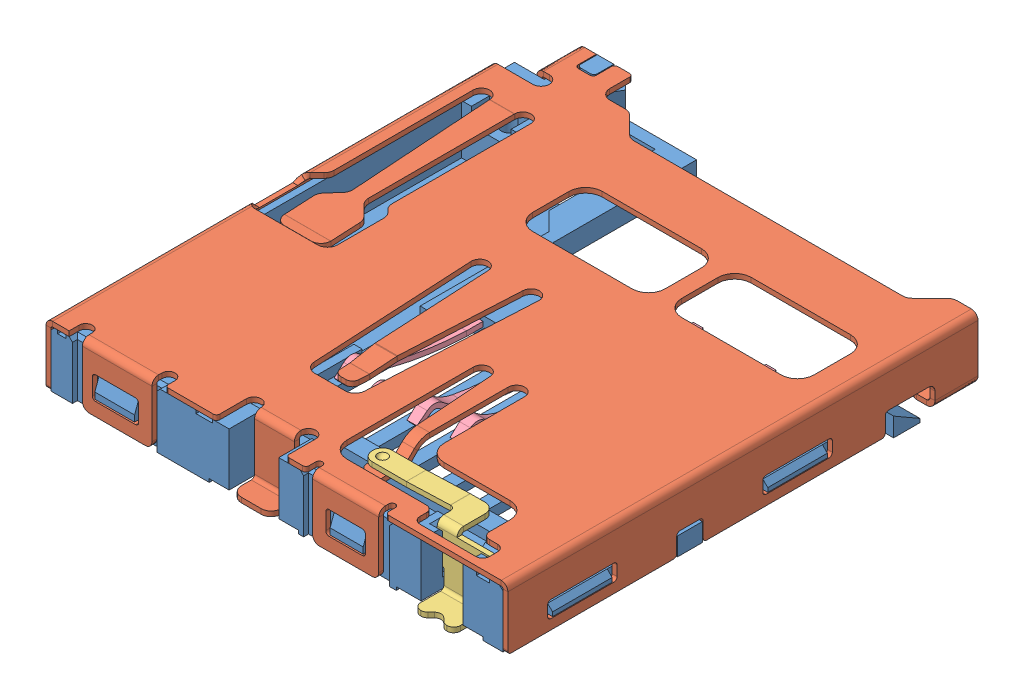
SolidWorks assembly microSD_Connector, configuration Default. Lengths in mm.
Overall size (14.1 1.9 15.45).
12 component instances, 5 part files, 11 mates.
Components (placement in the parent):
- microSD_Body-1: microSD_Body [Default] at origin size (14.1 1.85 15.2)
- microSD_Cover-1: microSD_Cover [Default] at (0 1.7 0) x (1 0 0) z (0 0 -1) size (13.95 1.9 15.2)
- microSD_Card_Detect-1: microSD_Card_Detect [Default] at (4.99 -0.05 7.4) size (4.45 1.9 2.05)
- microSD_Spring-2: microSD_Spring [Default] at (-3.85 1.125 6.9) x (-0.521999 -0.852946 0) z (0.852946 -0.521999 0) size (1.41 10.35 1.43) (hidden)
- microSD_Pin-1: microSD_Pin [11.15] at (5.725 -0.05 -2) x (0 0 1) z (-1 0 0) size (7.35 1.15 0.6)
- microSD_Pin-2: microSD_Pin [11.15] at (4.625 -0.05 -2) x (0 0 1) z (-1 0 0) size (7.35 1.15 0.6)
- microSD_Pin-3: microSD_Pin [11.35] at (3.525 -0.05 -2) x (0 0 1) z (-1 0 0) size (7.35 1.15 0.6)
- microSD_Pin-4: microSD_Pin [11.15] at (2.425 -0.05 -2) x (0 0 1) z (-1 0 0) size (7.35 1.15 0.6)
- microSD_Pin-5: microSD_Pin [11.35] at (1.325 -0.05 -2) x (0 0 1) z (-1 0 0) size (7.35 1.15 0.6)
- microSD_Pin-6: microSD_Pin [11.15] at (0.225 -0.05 -2) x (0 0 1) z (-1 0 0) size (7.35 1.15 0.6)
- microSD_Pin-7: microSD_Pin [10.75] at (-0.875 -0.05 -2) x (0 0 1) z (-1 0 0) size (7.25 1.15 0.6)
- microSD_Pin-8: microSD_Pin [11.15] at (-1.975 -0.05 -2) x (0 0 1) z (-1 0 0) size (7.35 1.15 0.6)
Mates (geometry in assembly coordinates):
- Coincident3: coincident anti-aligned: plane of microSD_Body-1 through (0 1.7 0) normal (0 1 0); plane of microSD_Cover-1 through (0 1.7 0) normal (0 -1 0)
- Coincident9: coincident anti-aligned: plane of microSD_Body-1 through (5.625 -0.001 6.8) normal (0 0 1); plane of microSD_Card_Detect-1 through (4.99 -0.05 6.8) normal (0 0 -1)
- Width5: width anti-aligned: plane of microSD_Body-1 through (4.355 -0.001 6.8) normal (1 0 0); plane of microSD_Body-1 through (5.625 -0.001 8.8) normal (-1 0 0); plane of microSD_Card_Detect-1 through (4.39 0.1 6.95) normal (-1 0 0); plane of microSD_Card_Detect-1 through (5.59 0.1 6.95) normal (1 0 0)
- Width6: width anti-aligned: plane of microSD_Body-1 through (-6.825 1.7 -7.6) normal (-1 0 0); plane of microSD_Body-1 through (6.825 1.7 -7.6) normal (1 0 0); plane of microSD_Cover-1 through (6.825 1.7 0) normal (-1 0 0); plane of microSD_Cover-1 through (-6.825 1.7 0) normal (1 0 0)
- Coincident11: coincident anti-aligned: plane of microSD_Body-1 through (0 0 7.45) normal (0 0 1); plane of microSD_Cover-1 through (0 1.7 7.45) normal (0 0 -1)
- Coincident12: coincident aligned: plane of microSD_Cover-1 through (0 1.85 0) normal (0 1 0); plane of microSD_Card_Detect-1 through (4.99 1.85 7.4) normal (0 1 0)
- Coincident13: coincident aligned: plane of microSD_Body-1 through (-4.725 -0.001 7) normal (0 0 -1); plane of microSD_Spring-2
- Concentric1: concentric: cylinder of microSD_Body-1 through (-3.85 1.125 5.5) axis (0 0 1) radius 0.275; point of microSD_Spring-2
- Coincident14: coincident: point of microSD_Body-1; point of microSD_Pin-1
- Coincident15: coincident: point of microSD_Body-1; point of microSD_Pin-1
- Coincident16: coincident anti-aligned: plane of microSD_Body-1 through (5.425 0.3 -7.601) normal (0 1 0); plane of microSD_Pin-1 through (5.425 0.3 -0.3) normal (0 -1 0)
